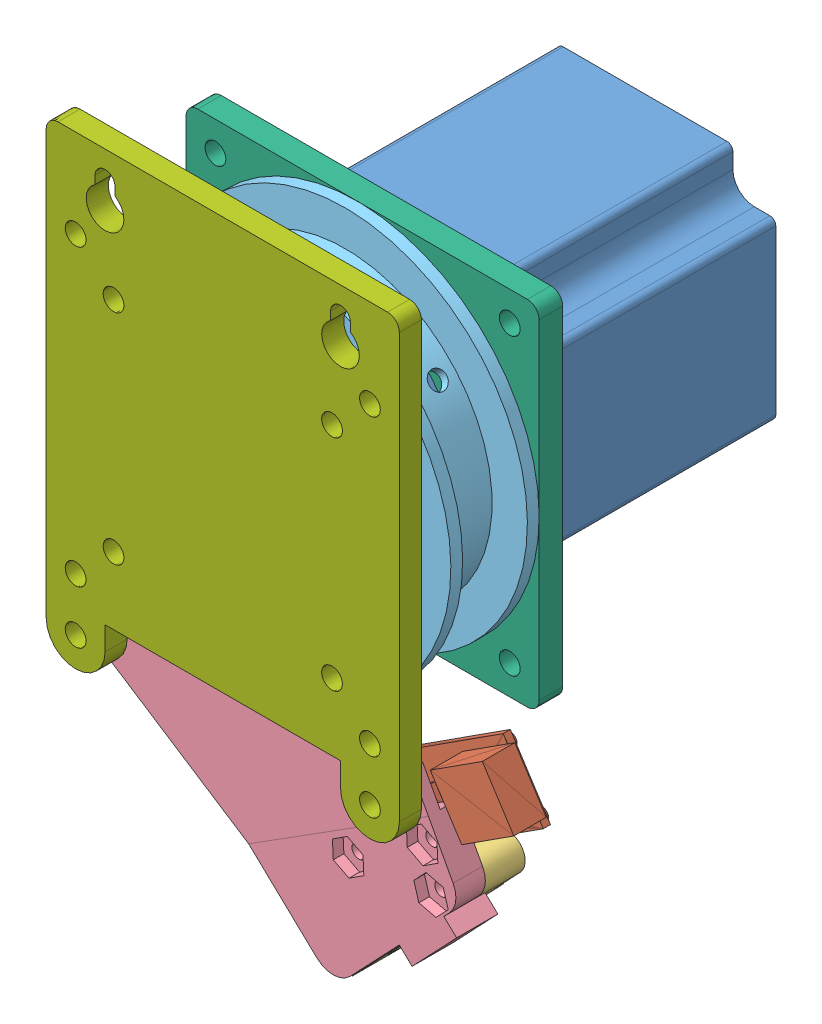
SolidWorks assembly rover_assembly4, configuration Default. Lengths in mm.
Overall size (138.22 150.7 91.12).
8 component instances, 7 part files, 17 mates.
Components (placement in the parent):
- anaheim_stepper_nema23-1: anaheim_stepper_nema23 [Default] at (3.6025 9.7468 4.1172) size (56.4 56.4 76.88)
- limit_assembly-1: limit_assembly [Default] at (-32.3084 -84.514 4.3563) x (0.68829 0.725435 0) z (0 0 -1) size (87.03 107.95 19.05)
  - mechanical_endstop-1: mechanical_endstop [Default] at (58.8161 21.2263 -22.6708) x (0.971653 0.236413 0) z (0 0 -1) size (41.88 19.5 9.76)
  - lever_bar-1: lever_bar [Default] at (59.5905 30.3176 -27.4208) size (38.1 7.62 15.24)
  - limit_plate4-1: limit_plate4 [Default] at (83.7195 -31.9124 -33.7708) size (87.03 107.95 19.05)
- string_pulley-1: string_pulley [Default] at (3.6025 9.7468 24.7871) x (-0.751113 -0.660173 0) z (0 0 -1) size (78.74 78.74 19.05)
- motor_mount-1: motor_mount [Default] at (3.6025 9.7468 8.9172) size (76.2 76.2 5.08)
- wall_plate-1: wall_plate [Default] at (3.6025 9.7468 44.1597) x (-1 0 0) z (0 0 -1) size (76.2 100.33 4.76)
Mates (geometry in assembly coordinates):
- Concentric1: concentric anti-aligned: cylinder of anaheim_stepper_nema23-1 through (3.6025 9.7468 10.5172) axis (0 0 -1) radius 19.05; cylinder of ? through (3.6025 9.7468 11.4572) axis (0 0 1) radius 25.4
- Concentric2: concentric aligned: cylinder of anaheim_stepper_nema23-1 through (3.6025 9.7468 29.9172) axis (0 0 -1) radius 3.175; cylinder of string_pulley-1 through (3.6025 9.7468 34.3121) axis (0 0 -1) radius 3.1115
- Distance1: distance = 1.27 mm anti-aligned: plane of ? through (3.5556 9.8648 13.9972) normal (0 0 1); plane of string_pulley-1 through (-25.7742 -16.464 15.2672) normal (0 0 -1)
- Concentric5: concentric aligned: cylinder of anaheim_stepper_nema23-1 through (3.6025 9.7468 29.9172) axis (0 0 -1) radius 3.175; cylinder of limit_assembly-1/limit_plate4-1 through (3.6025 9.7468 13.9972) axis (0 0 -1) radius 3.81
- Distance2: distance = 1.27 mm anti-aligned: plane of limit_assembly-1/limit_plate4-1 through (-28.2273 -33.4332 38.1272) normal (0 0 1); plane of wall_plate-1 through (3.6025 9.7468 39.3972) normal (0 0 -1)
- InPlace1: in place: plane of anaheim_stepper_nema23-1 through (-20.1525 33.5018 8.9172) normal (0 0 1); plane of ? through (0 0 8.9172) normal (0 0 1); moOrthogonalPlaneRef_w of anaheim_stepper_nema23-1 through (-20.1525 33.5018 8.9172) normal (0 0 1); plane of ? through (0 0 8.9172) normal (0 1 0); plane of anaheim_stepper_nema23-1 through (-20.1525 33.5018 8.9172) normal (0 0 1); plane of ? through (0 0 8.9172) normal (1 0 0); plane of anaheim_stepper_nema23-1 through (-20.1525 33.5018 8.9172) normal (0 0 1); unknown of motor_mount-1
- Coincident16: coincident aligned: plane of anaheim_stepper_nema23-1; plane of motor_mount-1
- Coincident17: coincident aligned: moOrthogonalPlaneRef_w of anaheim_stepper_nema23-1 through (3.6025 9.7468 8.9172) normal (0 1 0); plane of motor_mount-1 through (3.6025 9.7468 8.9172) normal (0 1 0)
- Coincident18: coincident anti-aligned: moOrthogonalPlaneRef_w of anaheim_stepper_nema23-1 through (3.6025 9.7468 8.9172) normal (-1 0 0); plane of motor_mount-1 through (3.6025 9.7468 8.9172) normal (1 0 0)
- InPlace2: in place: plane of anaheim_stepper_nema23-1 through (-20.1525 33.5018 -46.9628) normal (0 0 -1); plane of ? through (0 0 -46.9628) normal (0 0 -1); plane of anaheim_stepper_nema23-1 through (-20.1525 33.5018 -46.9628) normal (0 0 -1); unknown of ?; plane of anaheim_stepper_nema23-1 through (-20.1525 33.5018 -46.9628) normal (0 0 -1); plane of ? through (0 0 -46.9628) normal (-1 0 0); plane of anaheim_stepper_nema23-1 through (-20.1525 33.5018 -46.9628) normal (0 0 -1); unknown of ?
- Coincident19: coincident aligned: plane of anaheim_stepper_nema23-1; plane of wall_plate-1
- Coincident20: coincident aligned: moOrthogonalPlaneRef_w of anaheim_stepper_nema23-1 through (3.6025 9.7468 -46.9628) normal (0 1 0); plane of wall_plate-1
- Coincident21: coincident anti-aligned: moOrthogonalPlaneRef_w of anaheim_stepper_nema23-1 through (3.6025 9.7468 -46.9628) normal (1 0 0); plane of wall_plate-1 through (3.6025 9.7468 -46.9628) normal (-1 0 0)
- Distance3: distance = 25.4 mm anti-aligned: plane of wall_plate-1 through (3.6025 9.7468 39.3972) normal (0 0 -1); plane of motor_mount-1 through (3.6025 9.7468 13.9972) normal (0 0 1)
- Coincident1: coincident aligned: plane of motor_mount-1 through (41.7025 -28.3532 13.9972) normal (1 0 0); plane of wall_plate-1 through (41.7025 -28.3532 39.3972) normal (1 0 0)
- Coincident2: coincident aligned: plane of motor_mount-1 through (41.7025 -28.3532 13.9972) normal (0 -1 0); plane of wall_plate-1 through (-34.4975 -28.3532 39.3972) normal (0 -1 0)
- Coincident3: coincident anti-aligned: plane of limit_assembly-1/limit_plate4-1 through (-28.2107 -28.3532 38.1271) normal (0 1 0); plane of wall_plate-1 through (-34.4975 -28.3532 39.3972) normal (0 -1 0)
